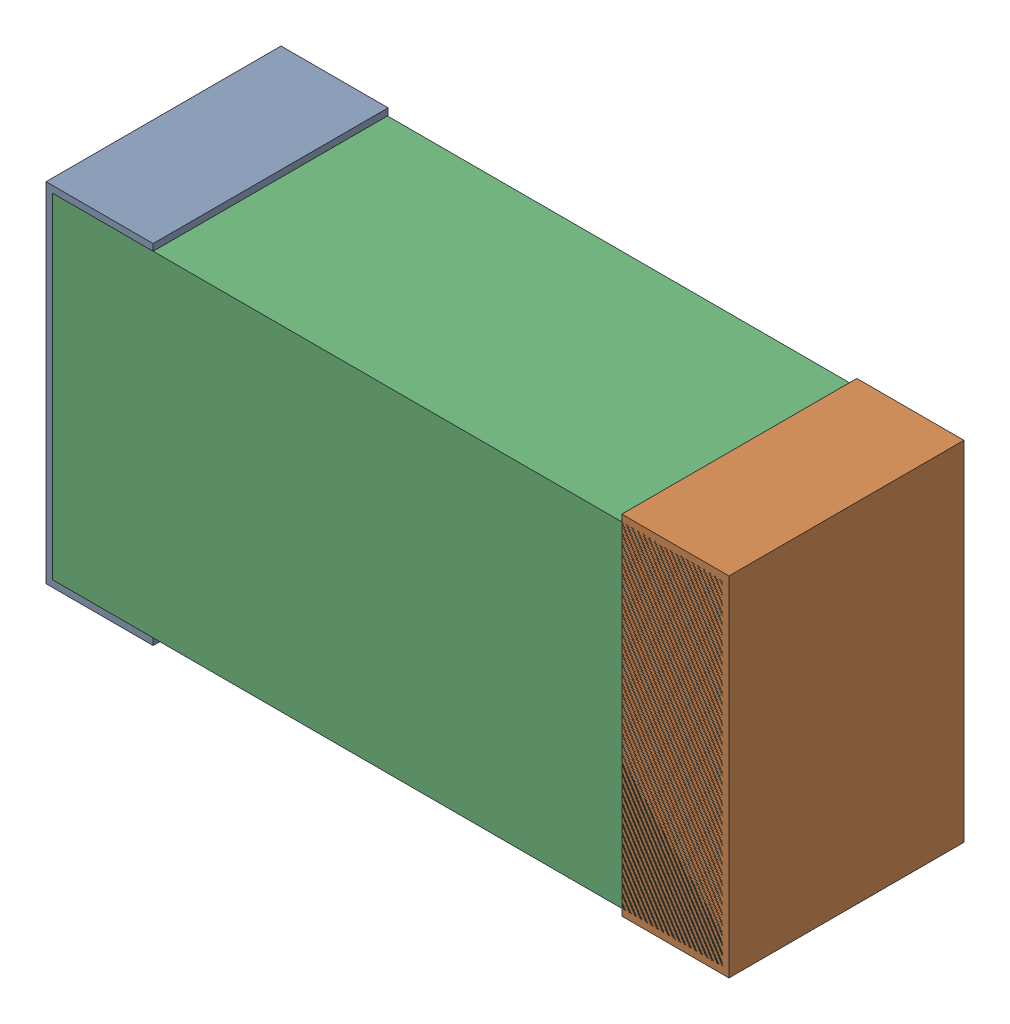
SolidWorks assembly C24, configuration Default. Lengths in mm.
Overall size (1.02 0.52 0.35).
6 component instances, 2 part files, 0 mates.
Components (placement in the parent):
- 870940480-1: 870940480 [Default] at (9.603 33.147 -1.9516) size (0.16 0.52 0.35)
  - Extruded-1: Extruded [Default] at origin size (0.16 0.52 0.35)
- 870940480-2: 870940480 [Default] at (10.463 33.147 -1.9516) size (0.16 0.52 0.35)
  - Extruded-1: Extruded [Default] at origin size (0.16 0.52 0.35)
- 870940640-1: 870940640 [Default] at (10.033 33.147 -1.9506) size (1 0.5 0.35)
  - Extruded_2-1: Extruded_2 [Default] at origin size (1 0.5 0.35)
